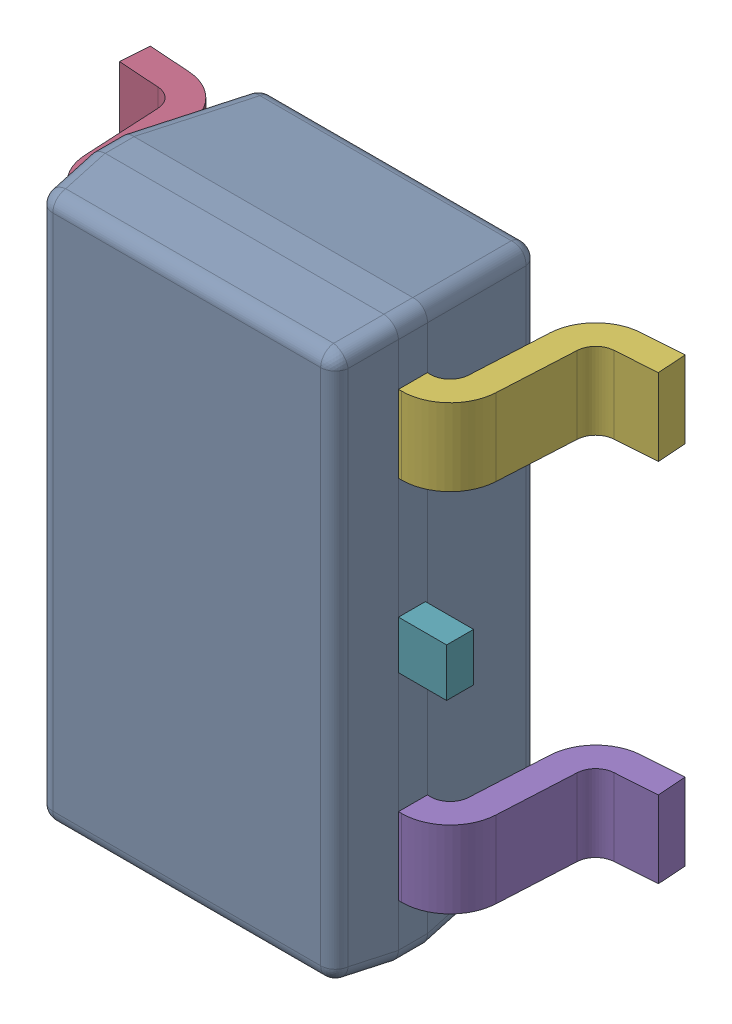
SolidWorks assembly 6348793248_1.step, configuration Default. Lengths in mm.
Overall size (2.8 2.9 1.2).
7 component instances, 3 part files, 0 mates.
Components (placement in the parent):
- BODY-SOT_1.step-11: BODY-SOT_1.step [Default] at (0 0 0.9) x (0 -1 0) z (-1 0 0) size (2.9 1.1 1.6)
- LEAD-SOT_1.step-51: LEAD-SOT_1.step [Default] at (-0.9395 -0.95 0.25) x (0 -1 0) z (-1 0 0) size (0.4 0.9 0.6)
- LEAD-SOT_1.step-52: LEAD-SOT_1.step [Default] at (-0.9395 0 0.25) x (0 -1 0) z (-1 0 0) size (0.4 0.9 0.6)
- LEAD-SOT_1.step-53: LEAD-SOT_1.step [Default] at (-0.9395 0.95 0.25) x (0 -1 0) z (-1 0 0) size (0.4 0.9 0.6)
- LEAD-SOT_1.step-54: LEAD-SOT_1.step [Default] at (0.9395 -0.95 0.25) x (0 1 0) z (1 0 0) size (0.4 0.9 0.6)
- LEAD-SOT_1.step-55: LEAD-SOT_1.step [Default] at (0.9395 0.95 0.25) x (0 1 0) z (1 0 0) size (0.4 0.9 0.6)
- LEAD-DUMMY_1.step-11: LEAD-DUMMY_1.step [Default] at (1.05 0 0.76) x (0 -1 0) z (-1 0 0) size (0.25 0.14 0.25)
